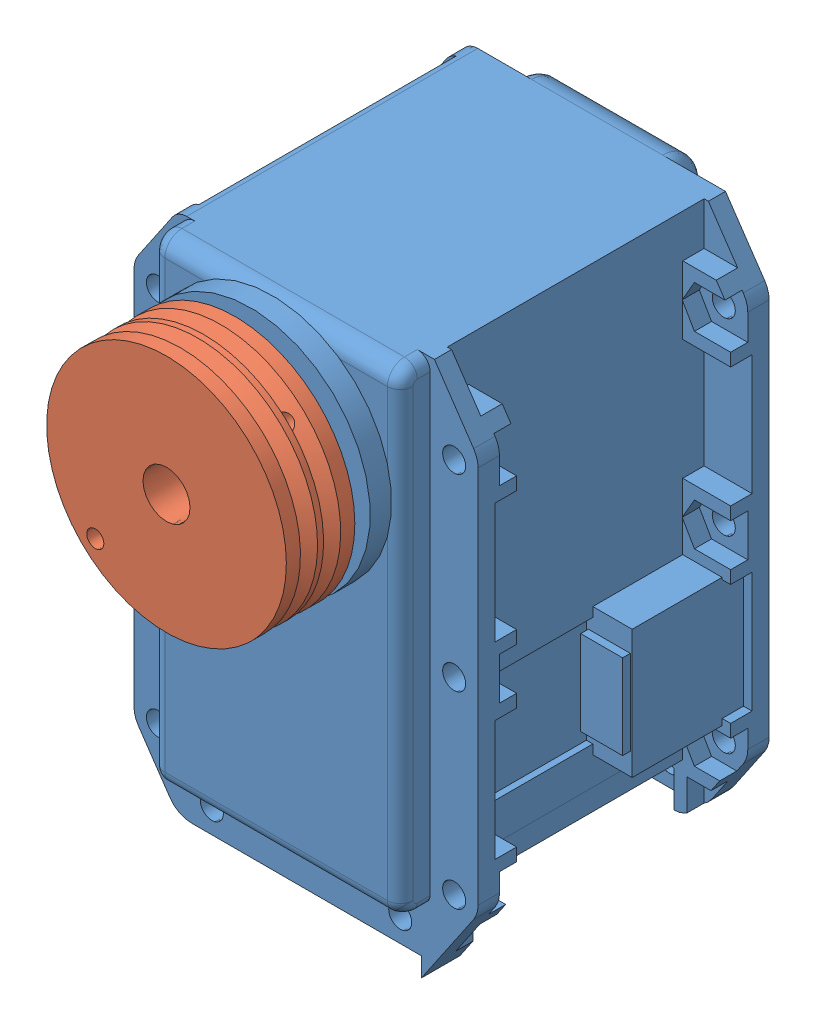
SolidWorks assembly actuator_w_pulley, configuration Default. Lengths in mm.
Overall size (40.2 70.14 55.3).
2 component instances, 2 part files, 2 mates.
Components (placement in the parent):
- MX-64-1: MX-64 [Default] at (-36.129 43.7784 -1.3323) size (40.2 64.34 50)
- Pulley_Actuator-1: Pulley_Actuator [Default] at (-36.129 43.7784 27.9677) x (0.720779 -0.693165 0) z (0 0 1) size (28 28 8)
Mates (geometry in assembly coordinates):
- Concentric1: concentric aligned: circle of MX-64-1; circle of Pulley_Actuator-1
- Coincident3: coincident anti-aligned: plane of MX-64-1 through (-31.129 43.7784 23.9677) normal (0 0 1); plane of Pulley_Actuator-1 through (-36.129 43.7784 23.9677) normal (0 0 -1)
